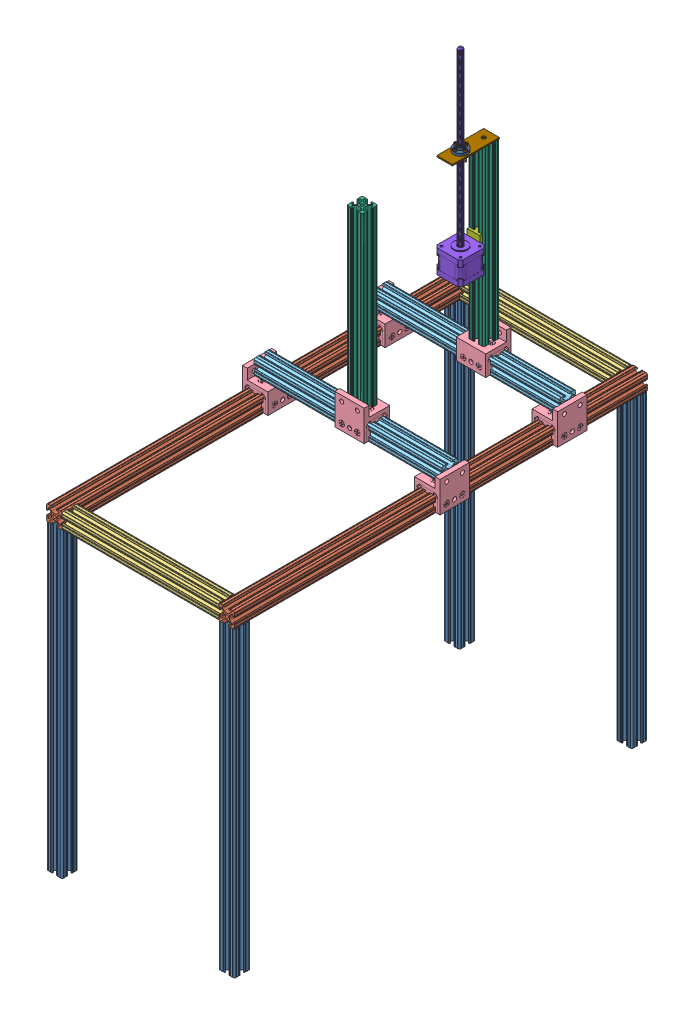
SolidWorks assembly FrameAssembly, configuration Default. Lengths in mm.
Overall size (321.15 989.41 670).
30 component instances, 12 part files, 56 mates.
Components (placement in the parent):
- 8020-height-49cm-1: 8020-height-49cm [Default] at (-65.1841 529.182 504.2732) x (1 0 0) z (0 -1 0) size (25.4 25.4 490)
- 8020-height-49cm-3: 8020-height-49cm [Default] at (-65.1841 39.182 1148.8732) x (-1 0 0) z (0 1 0) size (25.4 25.4 490)
- 8020-length-67cm-2: 8020-length-67cm [Default] at (-65.1841 541.882 491.5732) size (25.4 25.4 670)
- 8020-width-30point5cm-1: 8020-width-30point5cm [Default] at (-332.0841 541.882 504.2732) x (0 0 -1) z (1 0 0) size (25.4 25.4 254.2)
- 8020-width-30point5cm-2: 8020-width-30point5cm [Default] at (-332.0841 541.882 1148.8732) x (0 1 0) z (1 0 0) size (25.4 25.4 254.2)
- 8020-length-67cm-3: 8020-length-67cm [Default] at (-344.7841 541.882 491.5732) size (25.4 25.4 670)
- 8020-height-49cm-5: 8020-height-49cm [Default] at (-344.7841 529.182 504.2732) x (1 0 0) z (0 -1 0) size (25.4 25.4 490)
- 8020-height-49cm-6: 8020-height-49cm [Default] at (-344.7841 529.182 1148.8732) x (1 0 0) z (0 -1 0) size (25.4 25.4 490)
- 47065T953_ALUMINUM T-SLOTTED FRAMING EXTRUSION-1: 47065T953_ALUMINUM T-SLOTTED FRAMING EXTRUSION [47065T953] at (-344.9365 531.4172 621.6543) size (41.25 49.99 47.62)
- 47065T953_ALUMINUM T-SLOTTED FRAMING EXTRUSION-2: 47065T953_ALUMINUM T-SLOTTED FRAMING EXTRUSION [47065T953] at (-65.0317 531.4172 621.6543) x (-1 0 0) z (0 0 -1) size (41.25 49.99 47.62)
- 8020-x-30point5cm-1: 8020-x-30point5cm [Default] at (-357.6365 577.442 620.9668) x (0 0 -1) z (1 0 0) size (25.4 25.4 305)
- 47065T953_ALUMINUM T-SLOTTED FRAMING EXTRUSION-3: 47065T953_ALUMINUM T-SLOTTED FRAMING EXTRUSION [47065T953] at (-188.8474 566.9772 620.8144) x (0 0 1) z (-1 0 0) size (41.25 49.99 47.62)
- 8020-z-28cm-1: 8020-z-28cm [Default] at (-188.8474 880.302 620.8144) x (1 0 0) z (0 -1 0) size (25.4 25.4 280)
- 6798-1: 6798 [Default] at (-189.0404 733.7774 633.1842) x (0 0 -1) z (0 -1 0) size (11.94 20.57 47.37)
- Pololu Stepper with 280mm LeadScrew-1: Pololu Stepper with 280mm LeadScrew [Valor predeterminado] at (-188.9741 740.0919 658.3482) size (42.3 318.5 42.3)
- topPlate-1: topPlate [Default] at (-188.8474 880.302 645.9144) x (0 0 1) z (-1 0 0) size (76.2 2 25.4)
- TravelingNut-1: TravelingNut [Valor predeterminado] at (-188.9741 884.302 658.3482) x (0.764161 0 -0.645026) z (0.645026 0 0.764161) size (22 13.66 22)
- 91290A572_BLACK-OXIDE ALLOY STEEL SOCKET HEAD SCREW-1: 91290A572_BLACK-OXIDE ALLOY STEEL SOCKET HEAD SCREW [91290A572] at (-189.6591 871.302 666.451) x (-0.859683 0 -0.510827) z (0 -1 0) size (5.5 5.5 18.24)
- 90592A085_STEEL HEX NUT-1: 90592A085_STEEL HEX NUT [90592A085] at (-189.6591 879.102 666.451) x (0.874703 0 -0.48466) z (0.48466 0 0.874703) size (5.5 2.79 6.35)
- 90592A085_STEEL HEX NUT-2: 90592A085_STEEL HEX NUT [90592A085] at (-180.8713 879.102 659.0332) x (-0.48466 0 -0.874703) z (0.874703 0 -0.48466) size (5.5 2.79 6.35)
- 90592A085_STEEL HEX NUT-3: 90592A085_STEEL HEX NUT [90592A085] at (-188.2891 879.102 650.2453) x (-0.874703 0 0.48466) z (-0.48466 0 -0.874703) size (5.5 2.79 6.35)
- 90592A085_STEEL HEX NUT-4: 90592A085_STEEL HEX NUT [90592A085] at (-197.0769 879.102 657.6631) x (0.48466 0 0.874703) z (-0.874703 0 0.48466) size (5.5 2.79 6.35)
- 91290A572_BLACK-OXIDE ALLOY STEEL SOCKET HEAD SCREW-2: 91290A572_BLACK-OXIDE ALLOY STEEL SOCKET HEAD SCREW [91290A572] at (-180.8713 871.302 659.0332) x (-0.510827 0 0.859683) z (0 -1 0) size (5.5 5.5 18.24)
- 91290A572_BLACK-OXIDE ALLOY STEEL SOCKET HEAD SCREW-3: 91290A572_BLACK-OXIDE ALLOY STEEL SOCKET HEAD SCREW [91290A572] at (-188.2891 871.302 650.2453) x (0.859683 0 0.510827) z (0 -1 0) size (5.5 5.5 18.24)
- 91290A572_BLACK-OXIDE ALLOY STEEL SOCKET HEAD SCREW-4: 91290A572_BLACK-OXIDE ALLOY STEEL SOCKET HEAD SCREW [91290A572] at (-197.0769 871.302 657.6631) x (0.510827 0 -0.859683) z (0 -1 0) size (5.5 5.5 18.24)
- 47065T953_ALUMINUM T-SLOTTED FRAMING EXTRUSION-4: 47065T953_ALUMINUM T-SLOTTED FRAMING EXTRUSION [47065T953] at (-344.6317 531.4172 812.2015) size (41.25 49.99 47.62)
- 8020-x-30point5cm-2: 8020-x-30point5cm [Default] at (-357.3317 577.442 812.199) x (0 0 -1) z (1 0 0) size (25.4 25.4 305)
- 47065T953_ALUMINUM T-SLOTTED FRAMING EXTRUSION-6: 47065T953_ALUMINUM T-SLOTTED FRAMING EXTRUSION [47065T953] at (-65.3365 531.4172 812.2015) x (-1 0 0) z (0 0 -1) size (41.25 49.99 47.62)
- 47065T953_ALUMINUM T-SLOTTED FRAMING EXTRUSION-7: 47065T953_ALUMINUM T-SLOTTED FRAMING EXTRUSION [47065T953] at (-194.4587 566.9772 812.3514) x (0 0 -1) z (1 0 0) size (41.25 49.99 47.62)
- 8020-z-28cm-2: 8020-z-28cm [Default] at (-194.4587 880.302 812.3514) x (1 0 0) z (0 -1 0) size (25.4 25.4 280)
Mates (geometry in assembly coordinates):
- Coincident1: coincident anti-aligned: plane of 8020-height-50cm-3 through (-58.7677 529.182 1139.4634) normal (0 1 0); plane of 8020-length-67cm-2 through (-58.851 529.182 1161.5732) normal (0 -1 0)
- Coincident2: coincident aligned: plane of 8020-height-50cm-3 through (-52.4841 529.182 1158.4236) normal (1 0 0); plane of 8020-length-67cm-2 through (-52.4841 532.3316 1161.5732) normal (1 0 0)
- Coincident3: coincident aligned: plane of 8020-height-50cm-3 through (-58.851 529.182 1161.5732) normal (0 0 1); plane of 8020-length-67cm-2 through (-71.6005 532.4721 1161.5732) normal (0 0 1)
- Coincident4: coincident anti-aligned: plane of 8020-height-50cm-1 through (-71.6005 529.182 494.8634) normal (0 1 0); plane of 8020-length-67cm-2 through (-74.7345 529.182 1161.5732) normal (0 -1 0)
- Coincident5: coincident aligned: plane of 8020-height-50cm-1 through (-74.7345 39.182 491.5732) normal (0 0 -1); plane of 8020-length-67cm-2 through (-71.6005 532.4721 491.5732) normal (0 0 -1)
- Coincident6: coincident aligned: plane of 8020-height-50cm-1 through (-52.4841 39.182 494.7228) normal (1 0 0); plane of 8020-length-67cm-2 through (-52.4841 532.3316 1161.5732) normal (1 0 0)
- Coincident7: coincident anti-aligned: plane of 8020-length-67cm-2 through (-77.8841 535.5489 1161.5732) normal (-1 0 0); plane of 8020-width-30point5cm-1 through (-77.8841 532.4721 510.6896) normal (1 0 0)
- Coincident8: coincident aligned: plane of 8020-length-67cm-2 through (-71.6005 532.4721 491.5732) normal (0 0 -1); plane of 8020-width-30point5cm-1 through (-77.8841 532.3316 491.5732) normal (0 0 -1)
- Coincident9: coincident aligned: plane of 8020-length-67cm-2 through (-71.5172 554.582 1161.5732) normal (0 1 0); plane of 8020-width-30point5cm-1 through (-77.8841 554.582 494.7228) normal (0 1 0)
- Coincident10: coincident anti-aligned: plane of 8020-length-67cm-2 through (-77.8841 551.4324 1161.5732) normal (-1 0 0); plane of 8020-width-30point5cm-2 through (-77.8841 535.4656 1139.4634) normal (1 0 0)
- Coincident11: coincident aligned: plane of 8020-length-67cm-2 through (-71.5172 554.582 1161.5732) normal (0 1 0); plane of 8020-width-30point5cm-2 through (-77.8841 554.582 1139.3228) normal (0 1 0)
- Coincident12: coincident aligned: plane of 8020-length-67cm-2 through (-71.6005 532.4721 1161.5732) normal (0 0 1); plane of 8020-width-30point5cm-2 through (-77.8841 535.5488 1161.5732) normal (0 0 1)
- Coincident13: coincident aligned: plane of 8020-width-30point5cm-1 through (-77.8841 554.582 510.6063) normal (0 1 0); plane of 8020-length-67cm-3 through (-351.1172 554.582 1161.5732) normal (0 1 0)
- Coincident14: coincident aligned: plane of 8020-width-30point5cm-1 through (-77.8841 548.2151 491.5732) normal (0 0 -1); plane of 8020-length-67cm-3 through (-351.2005 532.4721 491.5732) normal (0 0 -1)
- Coincident15: coincident anti-aligned: plane of 8020-width-30point5cm-1 through (-332.0841 532.4721 510.6896) normal (-1 0 0); plane of 8020-length-67cm-3 through (-332.0841 532.3316 1161.5732) normal (1 0 0)
- Coincident16: coincident anti-aligned: plane of 8020-length-67cm-3 through (-338.451 529.182 1161.5732) normal (0 -1 0); plane of 8020-height-50cm-5 through (-351.2005 529.182 494.8634) normal (0 1 0)
- Coincident17: coincident aligned: plane of 8020-length-67cm-3 through (-351.2005 532.4721 491.5732) normal (0 0 -1); plane of 8020-height-50cm-5 through (-338.451 39.182 491.5732) normal (0 0 -1)
- Coincident18: coincident aligned: plane of 8020-length-67cm-3 through (-357.4841 535.5489 1161.5732) normal (-1 0 0); plane of 8020-height-50cm-5 through (-357.4841 39.182 497.9401) normal (-1 0 0)
- Coincident20: coincident aligned: plane of 8020-length-67cm-3 through (-351.2005 532.4721 1161.5732) normal (0 0 1); plane of 8020-height-50cm-6 through (-351.1172 39.182 1161.5732) normal (0 0 1)
- Coincident19: coincident aligned: plane of 8020-length-67cm-3 through (-357.4841 535.5489 1161.5732) normal (-1 0 0); plane of 8020-height-50cm-6 through (-357.4841 39.182 1158.4236) normal (-1 0 0)
- Coincident21: coincident anti-aligned: plane of 8020-length-67cm-3 through (-354.3345 529.182 1161.5732) normal (0 -1 0); plane of 8020-height-50cm-6 through (-351.2005 529.182 1139.4634) normal (0 1 0)
- Coincident22: coincident anti-aligned: plane of 8020-length-67cm-3 through (-332.0841 532.3316 1161.5732) normal (1 0 0); plane of 47065T953_ALUMINUM T-SLOTTED FRAMING EXTRUSION-1 through (-332.0841 531.4172 645.3398) normal (-1 0 0)
- Coincident23: coincident anti-aligned: plane of 8020-length-67cm-3 through (-335.2337 554.582 1161.5732) normal (0 1 0); plane of 47065T953_ALUMINUM T-SLOTTED FRAMING EXTRUSION-1 through (-341.7615 554.582 645.3398) normal (0 -1 0)
- LimitDistance1: limit distance = 490.7065 mm anti-aligned: plane of 47065T953_ALUMINUM T-SLOTTED FRAMING EXTRUSION-1 through (-365.5613 531.4172 645.4668) normal (0 0 1); plane of 8020-width-30point5cm-2 through (-77.8841 548.2151 1136.1732) normal (0 0 -1)
- Coincident24: coincident anti-aligned: plane of 47065T953_ALUMINUM T-SLOTTED FRAMING EXTRUSION-1 through (-365.5613 564.742 645.4668) normal (0 1 0); plane of 8020-x-30point5cm-1 through (-52.6365 564.742 614.6336) normal (0 -1 0)
- Coincident25: coincident anti-aligned: plane of 47065T953_ALUMINUM T-SLOTTED FRAMING EXTRUSION-1 through (-357.6365 558.392 669.8055) normal (1 0 0); plane of 8020-x-30point5cm-1 through (-357.6365 568.0321 627.3832) normal (-1 0 0)
- Distance2: distance = 11.8 mm aligned: plane of 8020-x-30point5cm-1 through (-52.6365 571.1089 633.6668) normal (0 0 1); plane of 47065T953_ALUMINUM T-SLOTTED FRAMING EXTRUSION-1 through (-365.5613 531.4172 645.4668) normal (0 0 1)
- Coincident28: coincident anti-aligned: plane of 8020-x-30point5cm-1 through (-52.6365 586.9924 633.6668) normal (0 0 1); plane of 47065T953_ALUMINUM T-SLOTTED FRAMING EXTRUSION-3 through (-212.5329 580.4646 633.6668) normal (0 0 -1)
- Coincident29: coincident anti-aligned: plane of 8020-x-30point5cm-1 through (-52.6365 590.142 627.2999) normal (0 1 0); plane of 47065T953_ALUMINUM T-SLOTTED FRAMING EXTRUSION-3 through (-212.5329 590.142 623.9894) normal (0 -1 0)
- LimitDistance2: limit distance = 144.9766 mm aligned: plane of 47065T953_ALUMINUM T-SLOTTED FRAMING EXTRUSION-3 through (-212.6599 566.9772 600.1896) normal (-1 0 0); plane of 8020-x-30point5cm-1 through (-357.6365 568.0321 627.3832) normal (-1 0 0)
- Coincident32: coincident anti-aligned: plane of 8020-z-28cm-1 through (-187.1916 600.302 625.3102) normal (0 0 1); plane of 6798-1 through (-191.5804 710.0919 625.3102) normal (0 0 -1)
- Coincident35: coincident anti-aligned: plane of 6798-1 through (-178.7534 710.0919 637.2482) normal (0 0 1); plane of Pololu Stepper with 280mm LeadScrew-1 through (-203.8741 718.0919 637.2482) normal (0 0 -1)
- Coincident36: coincident aligned: plane of 6798-1 through (-189.0404 710.0919 633.1842) normal (0 -1 0); plane of Pololu Stepper with 280mm LeadScrew-1 through (-188.9741 710.0919 658.3482) normal (0 -1 0)
- Distance5: distance = 10.7467 mm aligned: plane of 6798-1 through (-199.3274 710.0919 637.2482) normal (-1 0 0); plane of Pololu Stepper with 280mm LeadScrew-1 through (-210.0741 718.0919 673.2482) normal (-1 0 0)
- Distance7: distance = 2.22 mm aligned: plane of 6798-1 through (-199.3274 710.0919 637.2482) normal (-1 0 0); plane of 8020-z-28cm-1 through (-201.5474 600.302 630.3648) normal (-1 0 0)
- LimitDistance5: limit distance = 122.839 mm aligned: plane of 6798-1 through (-189.0404 757.4629 633.1842) normal (0 1 0); plane of 8020-z-28cm-1 through (-195.2638 880.302 611.4045) normal (0 1 0)
- Coincident47: coincident anti-aligned: plane of 8020-z-28cm-1 through (-195.2638 880.302 611.4045) normal (0 1 0); plane of topPlate-1 through (-188.8474 880.302 645.9144) normal (0 -1 0)
- Coincident48: coincident aligned: plane of 8020-z-28cm-1 through (-201.5474 600.302 614.4813) normal (-1 0 0); plane of topPlate-1 through (-201.5474 882.302 608.1144) normal (-1 0 0)
- Coincident49: coincident anti-aligned: line of 8020-z-28cm-1 through (-198.3978 880.302 608.1144) axis (1 0 0); line of topPlate-1 through (-176.1474 880.302 608.1144) axis (-1 0 0)
- Screw1: screw = 8 mm anti-aligned: axis of Pololu Stepper with 280mm LeadScrew-1 through (-188.9741 1026.0919 658.3482) axis (0 -1 0); line of TravelingNut-1 through (-188.9741 878.552 658.3482) axis (0 1 0)
- Concentric2: concentric aligned: cylinder of TravelingNut-1 through (-189.6591 878.552 666.451) axis (0 1 0) radius 1.5; circle of 91290A572_BLACK-OXIDE ALLOY STEEL SOCKET HEAD SCREW-1
- Coincident55: coincident anti-aligned: plane of TravelingNut-1 through (-188.9741 886.302 658.3482) normal (0 1 0); plane of 91290A572_BLACK-OXIDE ALLOY STEEL SOCKET HEAD SCREW-1 through (-189.6591 886.302 666.451) normal (0 -1 0)
- Screw2: screw = 0.5 aligned: line of 91290A572_BLACK-OXIDE ALLOY STEEL SOCKET HEAD SCREW-1 through (-189.6591 886.177 666.451) axis (0 -1 0); line of 90592A085_STEEL HEX NUT-1 through (-189.6591 880.302 666.451) axis (0 -1 0)
- Coincident56: coincident anti-aligned: plane of topPlate-1 through (-188.8474 880.302 645.9144) normal (0 -1 0); plane of 90592A085_STEEL HEX NUT-1 through (-192.8341 880.302 666.395) normal (0 1 0)
- Coincident59: coincident anti-aligned: plane of topPlate-1 through (-188.8474 882.302 645.9144) normal (0 1 0); plane of TravelingNut-1 through (-188.9741 882.302 658.3482) normal (0 -1 0)
- Coincident61: coincident anti-aligned: plane of 8020-length-67cm-3 through (-335.2337 554.582 1161.5732) normal (0 1 0); plane of 47065T953_ALUMINUM T-SLOTTED FRAMING EXTRUSION-4 through (-341.4567 554.582 835.887) normal (0 -1 0)
- Coincident62: coincident anti-aligned: plane of 8020-length-67cm-3 through (-357.4841 535.5489 1161.5732) normal (-1 0 0); plane of 47065T953_ALUMINUM T-SLOTTED FRAMING EXTRUSION-4 through (-357.4841 531.4172 835.887) normal (1 0 0)
- Coincident65: coincident anti-aligned: plane of 47065T953_ALUMINUM T-SLOTTED FRAMING EXTRUSION-4 through (-357.3317 558.392 860.3528) normal (1 0 0); plane of 8020-x-30point5cm-2 through (-357.3317 568.0321 818.6154) normal (-1 0 0)
- Coincident66: coincident anti-aligned: plane of 47065T953_ALUMINUM T-SLOTTED FRAMING EXTRUSION-4 through (-365.2565 564.742 836.014) normal (0 1 0); plane of 8020-x-30point5cm-2 through (-52.3317 564.742 821.7495) normal (0 -1 0)
- Distance9: distance = 11.115 mm aligned: plane of 8020-x-30point5cm-2 through (-52.3317 586.9924 824.899) normal (0 0 1); plane of 47065T953_ALUMINUM T-SLOTTED FRAMING EXTRUSION-4 through (-365.2565 531.4172 836.014) normal (0 0 1)
- Coincident69: coincident anti-aligned: plane of 8020-x-30point5cm-2 through (-52.3317 567.8916 799.499) normal (0 0 -1); plane of 47065T953_ALUMINUM T-SLOTTED FRAMING EXTRUSION-7 through (-170.7732 566.9772 799.499) normal (0 0 1)
- Coincident70: coincident anti-aligned: plane of 8020-x-30point5cm-2 through (-52.3317 590.142 818.5322) normal (0 1 0); plane of 47065T953_ALUMINUM T-SLOTTED FRAMING EXTRUSION-7 through (-170.7732 590.142 822.6638) normal (0 -1 0)
- Concentric3: concentric anti-aligned: circle of 47065T953_ALUMINUM T-SLOTTED FRAMING EXTRUSION-3; circle of 8020-z-28cm-1
- Coincident71: coincident anti-aligned: plane of 47065T953_ALUMINUM T-SLOTTED FRAMING EXTRUSION-3 through (-212.6599 600.302 600.1896) normal (0 1 0); plane of 8020-z-28cm-1 through (-195.2638 600.302 611.4045) normal (0 -1 0)
- Concentric4: concentric aligned: cylinder of 47065T953_ALUMINUM T-SLOTTED FRAMING EXTRUSION-7 through (-194.4587 566.9772 812.3514) axis (0 1 0) radius 3.3655; cylinder of 8020-z-28cm-2 through (-194.4587 600.302 812.3514) axis (0 1 0) radius 2.6035
- Coincident72: coincident anti-aligned: plane of 47065T953_ALUMINUM T-SLOTTED FRAMING EXTRUSION-7 through (-170.6462 600.302 832.9762) normal (0 1 0); plane of 8020-z-28cm-2 through (-200.8751 600.302 802.9416) normal (0 -1 0)
